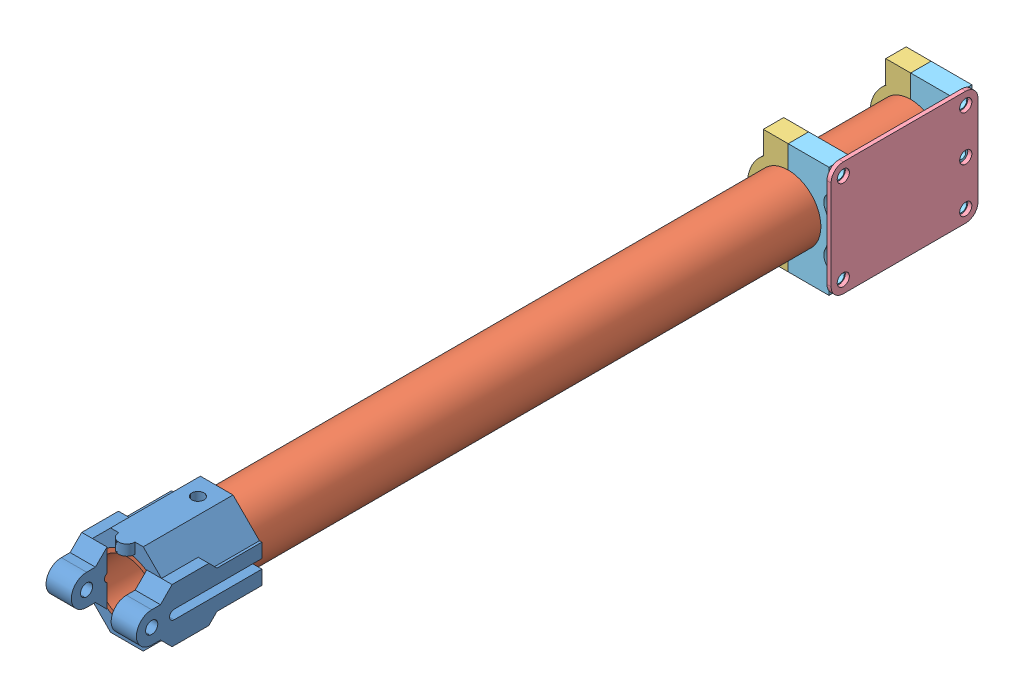
SolidWorks assembly TayDrone, configuration Default. Lengths in mm.
Overall size (22.14 28 208.75).
7 component instances, 5 part files, 17 mates.
Components (placement in the parent):
- ArmCopterAttachement-1: ArmCopterAttachement [Default] at (-4.6198 22.3276 12.456) size (22.14 22.14 30.75)
- Carbon tube-1: Carbon tube [Default] at (-4.6198 22.3276 -165.544) x (0 -1 0) z (-1 0 0) size (16 200 16)
- Lowerclamp-1: Lowerclamp [Default] at (-4.6198 22.3276 -132.544) x (0 -1 0) z (0 0 1) size (27.2 10 5)
- plate-1: plate [Default] at (5.3802 8.3276 -127.044) x (0 0 -1) z (0 -1 0) size (36 1 28)
- Upperclamp-1: Upperclamp [Default] at (-4.6198 22.3287 -132.544) x (0 -1 0) z (0 0 1) size (27.2 10 5)
- Upperclamp-2: Upperclamp [Default] at (-4.6198 22.3287 -162.544) x (0 -1 0) z (0 0 1) size (27.2 10 5)
- Lowerclamp-2: Lowerclamp [Default] at (-4.6198 22.3276 -162.544) x (0 -1 0) z (0 0 1) size (27.2 10 5)
Mates (geometry in assembly coordinates):
- Concentric1: concentric aligned: cylinder of ArmCopterAttachement-1 through (-4.6198 22.3276 34.456) axis (0 0 -1) radius 8; cylinder of Carbon tube-1 through (-4.6198 22.3276 34.456) axis (0 0 -1) radius 8
- Coincident1: coincident anti-aligned: plane of ArmCopterAttachement-1 through (-4.6198 22.3276 34.456) normal (0 0 -1); plane of Carbon tube-1 through (-4.6198 22.3276 34.456) normal (0 0 1)
- Coincident2: coincident anti-aligned: plane of Upperclamp-2 through (-4.6198 22.3287 -157.544) normal (-1 0 0); plane of Lowerclamp-2 through (-4.6198 22.3276 -157.544) normal (1 0 0)
- Concentric2: concentric anti-aligned: cylinder of Upperclamp-2 through (305.3802 11.3276 -160.044) axis (-1 0 0) radius 1.25; cylinder of Lowerclamp-2 through (-14.6198 11.3276 -160.044) axis (1 0 0) radius 1
- Coincident3: coincident aligned: plane of Upperclamp-2 through (-4.6198 22.3287 -162.544) normal (0 0 -1); plane of Lowerclamp-2 through (-4.6198 22.3276 -162.544) normal (0 0 -1)
- Coincident4: coincident aligned: plane of Lowerclamp-1 through (-4.6198 22.3276 -132.544) normal (0 0 -1); plane of Upperclamp-1 through (-4.6198 22.3287 -132.544) normal (0 0 -1)
- Concentric3: concentric anti-aligned: cylinder of Lowerclamp-1 through (-14.6198 11.3276 -130.044) axis (1 0 0) radius 1; cylinder of Upperclamp-1 through (305.3802 11.3276 -130.044) axis (-1 0 0) radius 1.25
- Coincident5: coincident anti-aligned: plane of Lowerclamp-1 through (-4.6198 22.3276 -127.544) normal (1 0 0); plane of Upperclamp-1 through (-4.6198 22.3287 -127.544) normal (-1 0 0)
- Coincident6: coincident anti-aligned: plane of plate-1 through (5.3802 11.3276 -130.044) normal (-1 0 0); plane of Upperclamp-1 through (5.3802 22.3287 -127.544) normal (1 0 0)
- Concentric6: concentric aligned: cylinder of plate-1 through (6.3802 11.3276 -130.044) axis (-1 0 0) radius 1.5; cylinder of Upperclamp-1 through (305.3802 11.3276 -130.044) axis (-1 0 0) radius 1.25
- Concentric7: concentric aligned: cylinder of plate-1 through (6.3802 33.3276 -130.044) axis (-1 0 0) radius 1.5; circle of Upperclamp-1
- Concentric8: concentric anti-aligned: cylinder of plate-1 through (6.3802 11.3276 -160.044) axis (-1 0 0) radius 1.5; circle of Upperclamp-2
- Parallel1: parallel aligned: plane of ArmCopterAttachement-1 through (6.4513 26.3276 34.456) normal (1 0 0); plane of plate-1 through (6.3802 11.3276 -130.044) normal (1 0 0)
- Distance1: distance = 140 mm anti-aligned: plane of Upperclamp-1 through (-4.6198 22.3287 -127.544) normal (0 0 1); plane of ArmCopterAttachement-1 through (-4.6198 22.3276 12.456) normal (0 0 -1)
- Concentric9: concentric aligned: cylinder of Carbon tube-1 through (-4.6198 22.3276 34.456) axis (0 0 -1) radius 8; cylinder of Lowerclamp-2 through (-4.6198 22.3276 -157.544) axis (0 0 -1) radius 8
- Parallel2: parallel anti-aligned: cylinder of Carbon tube-1 through (3.3802 22.3276 -156.9804) axis (-1 0 0) radius 1; cylinder of Upperclamp-2 through (-4.6198 22.3287 -160.044) axis (1 0 0) radius 1
- Coincident7: coincident anti-aligned: plane of plate-1 through (5.3802 11.3276 -130.044) normal (-1 0 0); plane of Upperclamp-2 through (5.3802 22.3287 -157.544) normal (1 0 0)
